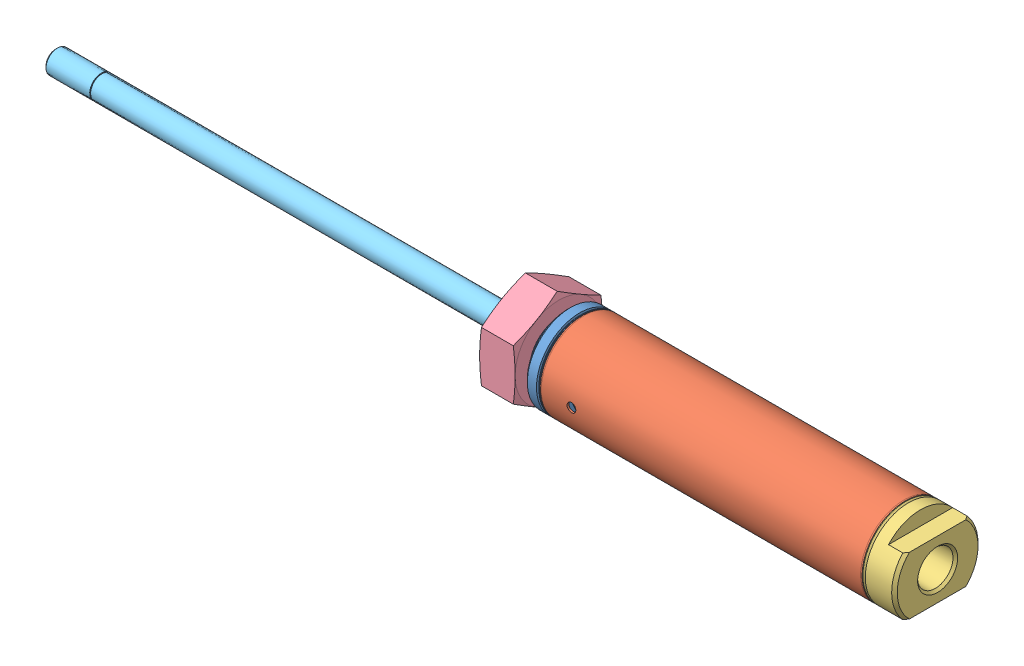
SolidWorks assembly 061_5-EE3_2_14, configuration Default. Lengths in mm.
Overall size (240.28 27.57 24.08).
5 component instances, 5 part files, 2 mates.
Components (placement in the parent):
- _06000-3_rod_guide-1: _06000-3_rod_guide [Default] at origin size (28.57 23.52 23.52)
- _06-3.46752C-1: _06-3.46752C [Default] at (16.51 0 0) size (89.43 23.52 23.52)
- _060000_rear_head-1: _060000_rear_head [Default] at (98.933 0 0) size (14.35 23.52 23.52)
- _D-9-1: _D-9 [Default] at (10.1092 0 0) x (0 0 -1) z (1 0 0) size (23.88 27.57 9.65)
- _C-061.5-EE30_rod-1: _C-061.5-EE30_rod [Default] at (-114.3 0 0) x (1 0 0) z (0 -0.078586 -0.996907) size (187.83 22.39 22.39)
Mates (geometry in assembly coordinates):
- Concentric1: concentric aligned: cylinder of _06-3.46752C-1 through (104.5845 0 0) axis (-1 0 0) radius 11.7602; cylinder of _C-061.5-EE30_rod-1 through (60.833 0 0) axis (-1 0 0) radius 11.1951
- LimitDistance1: limit distance = 38.1 mm anti-aligned: plane of _C-061.5-EE30_rod-1 through (60.833 -11.1604 0.8798) normal (1 0 0); plane of _060000_rear_head-1 through (98.933 0 0) normal (-1 0 0)
